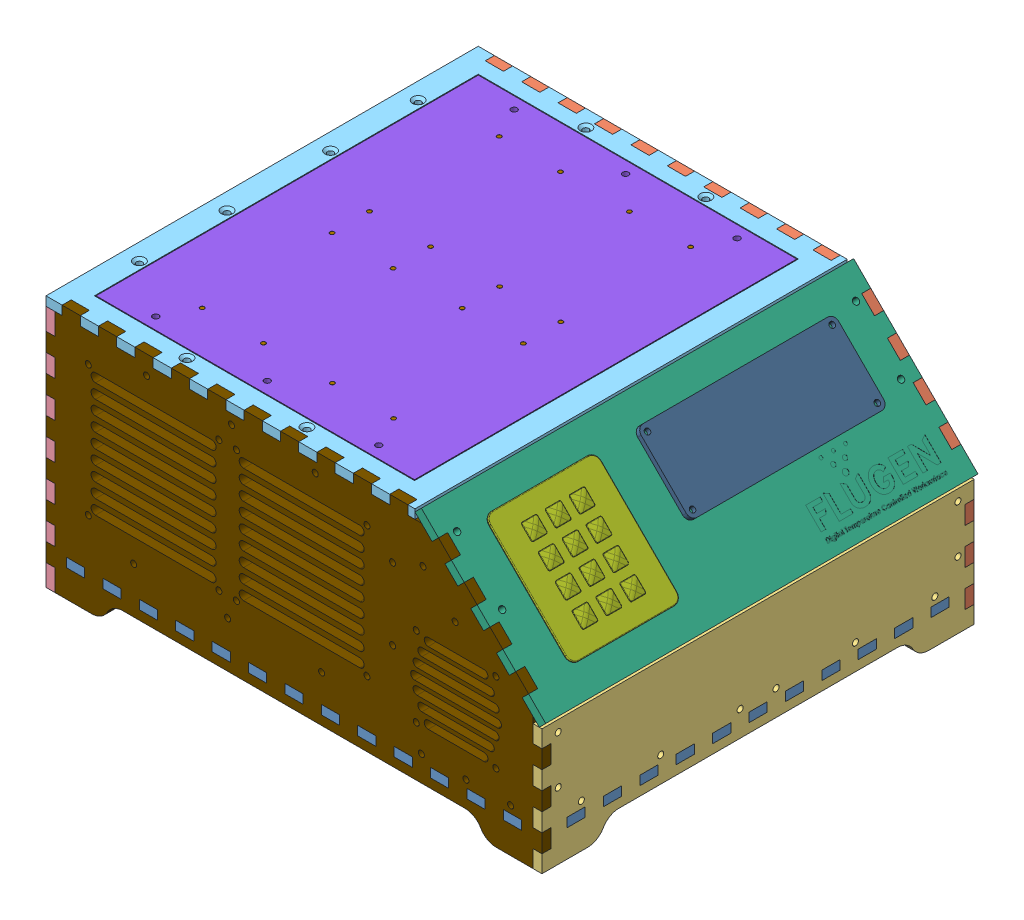
SolidWorks assembly REV 4 FINAL, configuration Default. Lengths in mm.
Overall size (313.8 160.95 271.43).
121 component instances, 55 part files, 109 mates.
Components (placement in the parent):
- Bottom R4-1: Bottom R4 [Default] at (-523.6995 354.7176 400.1225) x (1 0 0) z (0 -1 0) size (311.43 271.43 5.71)
- Side R4-2: Side R4 [Default] at (104.8725 308.9994 422.9797) size (311.43 158.58 5.71)
- Front R4-1: Front R4 [Default] at (420.9905 -621.4044 400.1225) x (0 1 0) z (1 0 0) size (78.82 271.43 5.71)
- Back R4-1: Back R4 [Default] at (115.2765 1867.4724 717.2667) x (0 -1 0) z (1 0 0) size (152.86 271.43 5.71)
- Top R4-1: Top R4 [Default] at (1495.1765 490.4374 717.2667) x (-1 0 0) z (0 -1 0) size (231.68 271.43 5.71)
- Console R4-1: Console R4 [Default] at (-380.8231 1224.6196 400.1222) x (0.707107 -0.707107 0) z (-0.707107 -0.707107 0) size (110.42 271.43 5.71)
- Peltier Assembly 3.0-1: Peltier Assembly 3.0 [Default] at (230.9915 490.4374 558.6945) x (-1 0 0) z (0 0 1) size (200 67.45 240)
  - Heatsink 3.0-1: Heatsink 3.0 [Default] at (-40.875 6 -52.5) x (-1 0 0) z (0 0 -1) size (78.2 61.32 89)
  - Heatsink 3.0-2: Heatsink 3.0 [Default] at (40.875 6 52.5) x (-1 0 0) z (0 0 -1) size (78.2 61.32 89)
  - Heatsink 3.0-3: Heatsink 3.0 [Default] at (-40.875 6 52.5) x (-1 0 0) z (0 0 -1) size (78.2 61.32 89)
  - Heatsink 3.0-4: Heatsink 3.0 [Default] at (40.875 6 -52.5) x (-1 0 0) z (0 0 -1) size (78.2 61.32 89)
  - Cold plate 2.0-1: Cold plate 2.0 [Default] at (-100 0 -220) x (0 0 1) z (0 1 0) size (240 200 3)
  - 91772A162_Passivated 18-8 Stainless Steel Pan Head Phillips Screw-1: 91772A162_Passivated 18-8 Stainless Steel Pan Head Phillips Screw [91772A162] at (21.675 0 93.25) x (0.999996 0 0.002747) z (0 1 0) size (6.86 6.86 16.79)
  - 91772A162_Passivated 18-8 Stainless Steel Pan Head Phillips Screw-2: 91772A162_Passivated 18-8 Stainless Steel Pan Head Phillips Screw [91772A162] at (-21.675 0 93.25) x (0.999996 0 0.002747) z (0 1 0) size (6.86 6.86 16.79)
  - 91772A162_Passivated 18-8 Stainless Steel Pan Head Phillips Screw-3: 91772A162_Passivated 18-8 Stainless Steel Pan Head Phillips Screw [91772A162] at (-60.075 0 93.25) x (0.996452 0 -0.084158) z (0 1 0) size (6.86 6.86 16.79)
  - 91772A162_Passivated 18-8 Stainless Steel Pan Head Phillips Screw-4: 91772A162_Passivated 18-8 Stainless Steel Pan Head Phillips Screw [91772A162] at (60.075 0 93.25) x (0.999996 0 0.002747) z (0 1 0) size (6.86 6.86 16.79)
  - 91772A162_Passivated 18-8 Stainless Steel Pan Head Phillips Screw-5: 91772A162_Passivated 18-8 Stainless Steel Pan Head Phillips Screw [91772A162] at (21.675 0 11.75) x (0.999996 0 0.002747) z (0 1 0) size (6.86 6.86 16.79)
  - 91772A162_Passivated 18-8 Stainless Steel Pan Head Phillips Screw-6: 91772A162_Passivated 18-8 Stainless Steel Pan Head Phillips Screw [91772A162] at (-21.675 0 11.75) x (0.999996 0 0.002747) z (0 1 0) size (6.86 6.86 16.79)
  - 91772A162_Passivated 18-8 Stainless Steel Pan Head Phillips Screw-7: 91772A162_Passivated 18-8 Stainless Steel Pan Head Phillips Screw [91772A162] at (-60.075 0 11.75) x (0.999996 0 0.002747) z (0 1 0) size (6.86 6.86 16.79)
  - 91772A162_Passivated 18-8 Stainless Steel Pan Head Phillips Screw-8: 91772A162_Passivated 18-8 Stainless Steel Pan Head Phillips Screw [91772A162] at (21.675 0 -11.75) x (0.999996 0 0.002747) z (0 1 0) size (6.86 6.86 16.79)
  - 91772A162_Passivated 18-8 Stainless Steel Pan Head Phillips Screw-9: 91772A162_Passivated 18-8 Stainless Steel Pan Head Phillips Screw [91772A162] at (60.075 0 11.75) x (0.999996 0 0.002747) z (0 1 0) size (6.86 6.86 16.79)
  - 91772A162_Passivated 18-8 Stainless Steel Pan Head Phillips Screw-10: 91772A162_Passivated 18-8 Stainless Steel Pan Head Phillips Screw [91772A162] at (-21.675 0 -11.75) x (0.999996 0 0.002747) z (0 1 0) size (6.86 6.86 16.79)
  - 91772A162_Passivated 18-8 Stainless Steel Pan Head Phillips Screw-11: 91772A162_Passivated 18-8 Stainless Steel Pan Head Phillips Screw [91772A162] at (60.075 0 -11.75) x (0.999996 0 0.002747) z (0 1 0) size (6.86 6.86 16.79)
  - 91772A162_Passivated 18-8 Stainless Steel Pan Head Phillips Screw-12: 91772A162_Passivated 18-8 Stainless Steel Pan Head Phillips Screw [91772A162] at (-60.075 0 -11.75) x (0.999996 0 0.002747) z (0 1 0) size (6.86 6.86 16.79)
  - 91772A162_Passivated 18-8 Stainless Steel Pan Head Phillips Screw-13: 91772A162_Passivated 18-8 Stainless Steel Pan Head Phillips Screw [91772A162] at (60.075 0 -93.25) x (0.999996 0 0.002747) z (0 1 0) size (6.86 6.86 16.79)
  - 91772A162_Passivated 18-8 Stainless Steel Pan Head Phillips Screw-14: 91772A162_Passivated 18-8 Stainless Steel Pan Head Phillips Screw [91772A162] at (21.675 0 -93.25) x (0.999996 0 0.002747) z (0 1 0) size (6.86 6.86 16.79)
  - 91772A162_Passivated 18-8 Stainless Steel Pan Head Phillips Screw-15: 91772A162_Passivated 18-8 Stainless Steel Pan Head Phillips Screw [91772A162] at (-21.675 0 -93.25) x (0.893935 0 0.448197) z (0 1 0) size (6.86 6.86 16.79)
  - 91772A162_Passivated 18-8 Stainless Steel Pan Head Phillips Screw-16: 91772A162_Passivated 18-8 Stainless Steel Pan Head Phillips Screw [91772A162] at (-60.075 0 -93.25) x (0.970194 0 -0.242331) z (0 1 0) size (6.86 6.86 16.79)
  - Acrylic seperator-1: Acrylic seperator [Default] at (100 3 220) x (0 0 -1) z (0 1 0) size (240 200 3)
- PSU-1: PSU [Default] at (115.2765 360.4326 440.1944) x (0 0 1) z (-1 0 0) size (87 40 205)
- PSU adapter board-1: PSU adapter board [Default] at (368.0265 364.7526 482.5694) x (0 0 -1) z (1 0 0) size (90 17.46 103.75)
- Hot area seperator-1: Hot area seperator [Default] at (231.2577 402.6176 483.6944) x (0 0 1) z (-1 0 0) size (110 3.1 220.53)
- Hot area seperator2-1: Hot area seperator2 [Default] at (231.2577 380.2176 538.6944) size (220.53 51 3.1)
- Hot area seperator3-1: Hot area seperator3 [Default] at (337.674 419.7176 558.6947) x (0 0 -1) z (1 0 0) size (260 130 3.1)
- F9-1: F9 [Default] at (243.6345 385.427 608.0401) x (-1 0 0) z (0 0 1) size (93.27 26.59 93.52)
  - F9.STEP-1: F9.STEP [Default] at origin size (93.27 26.59 93.52)
    - F9 body.STEP-1: F9 body.STEP [Default] at (-78.1983 5.7094 50.7544) size (92.01 26.59 92.01)
    - F9 fan.STEP-1: F9 fan.STEP [Default] at (-74.2115 10.4094 -44.9134) x (-0.083202 0 0.996533) z (-0.996533 0 -0.083202) size (86.63 20 86.36)
- F9-2: F9 [Default] at (150.6345 385.427 608.0401) x (-1 0 0) z (0 0 1) size (93.27 26.59 93.52)
  - F9.STEP-1: F9.STEP [Default] at origin size (93.27 26.59 93.52)
    - F9 body.STEP-1: F9 body.STEP [Default] at (-78.1983 5.7094 50.7544) size (92.01 26.59 92.01)
    - F9 fan.STEP-1: F9 fan.STEP [Default] at (-74.2115 10.4094 -44.9134) x (-0.083202 0 0.996533) z (-0.996533 0 -0.083202) size (86.63 20 86.36)
- Side R4_no_vent-1: Side R4_no_vent [Default] at (104.8764 309.0049 688.6942) size (311.43 158.58 5.71)
- Cold plate bracket-1: Cold plate bracket [Default] at (310.9915 484.4374 428.6947) x (0 0 -1) z (-1 0 0) size (24 12.29 160)
- Cold plate bracket-2: Cold plate bracket [Default] at (150.9915 484.4374 688.6942) x (0 0 1) z (1 0 0) size (24 12.29 160)
- Cold plate rear bracket-1: Cold plate rear bracket [Default] at (120.9915 484.7224 676.1946) x (0 1 0) z (0 0 -1) size (24 9.5 115)
- Cold plate rear bracket-2: Cold plate rear bracket [Default] at (120.9915 484.7224 556.1946) x (0 1 0) z (0 0 -1) size (24 9.5 115)
- HBridge Assembly-1: HBridge Assembly [Default] at (374.4563 378.022 646.7043) x (1 0 0) z (0 1 0) size (55.5 50 87)
  - BTS7960 H-Bridge Module-1: BTS7960 H-Bridge Module [Default] at (-3.9323 23.7652 53.8628) size (51.5 49.9 42)
    - BTS7960 H-Bridge Module.step-1: BTS7960 H-Bridge Module.step [Default] at origin size (51.5 49.9 42)
      - 2Pos Terminal Block_001.step-1: 2Pos Terminal Block_001.step [Default] at (0.8 20 1.6) x (0 1 0) z (0 0 1) size (10 10.4 16.75)
      - Body_001.step-1: Body_001.step [Default] at origin size (49.5 49.8 1.6)
      - 2Pos Terminal Block_002.step-1: 2Pos Terminal Block_002.step [Default] at (10.7 20 1.6) x (0 1 0) z (0 0 1) size (10 10.4 16.75)
      - Capacitor_001.step-1: Capacitor_001.step [Default] at (-10.7672 19.837 1.6) x (0 -1 0) z (-1 0 0) size (10.12 17.5 10.12)
      - BTN7960_001.step-1: BTN7960_001.step [Default] at (5.9321 -1.893 1.6) size (10 15.38 4.4)
      - BTN7960_002.step-1: BTN7960_002.step [Default] at (-5.9827 -1.8968 1.6) size (10 15.38 4.4)
      - SOJ 20_001.step-1: SOJ 20_001.step [Default] at (17.2939 -12.0721 1.6) x (0 -1 0) z (0 0 1) size (10.85 12.9 2.4)
      - 2x4 Male Header_001.step-1: 2x4 Male Header_001.step [Default] at (5.8669 -22.8725 1.6) size (10.16 5.08 11.3)
      - Fillet.step-1: Fillet.step [Default] at origin size (51.5 31.77 22.9)
      - M2.5x6-Screw.step-1: M2.5x6-Screw.step [Default] at (-13.3 -2.4 2) size (4.5 4.5 6)
      - M2.5x6-Screw.step-2: M2.5x6-Screw.step [Default] at (13.7 -2.4 2) size (4.5 4.5 6)
      - 0805 Resistor_001.step-1: 0805 Resistor_001.step [Default] at (9.9588 -15.7217 1.6) x (0 -1 0) z (0 0 1) size (2 1.25 0.5)
      - 0805 Resistor_002.step-1: 0805 Resistor_002.step [Default] at (7.9588 -15.7217 1.6) x (0 -1 0) z (0 0 1) size (2 1.25 0.5)
      - 0805 Resistor_003.step-1: 0805 Resistor_003.step [Default] at (5.9588 -15.7217 1.6) x (0 -1 0) z (0 0 1) size (2 1.25 0.5)
      - 0805 Resistor_004.step-1: 0805 Resistor_004.step [Default] at (3.9588 -15.7217 1.6) x (0 -1 0) z (0 0 1) size (2 1.25 0.5)
      - 0805 Resistor_005.step-1: 0805 Resistor_005.step [Default] at (1.9588 -15.7217 1.6) x (0 -1 0) z (0 0 1) size (2 1.25 0.5)
      - 0805 Resistor_006.step-1: 0805 Resistor_006.step [Default] at (-0.0412 -15.7217 1.6) x (0 -1 0) z (0 0 1) size (2 1.25 0.5)
      - 0805 Resistor_007.step-1: 0805 Resistor_007.step [Default] at (-2.0412 -15.7217 1.6) x (0 -1 0) z (0 0 1) size (2 1.25 0.5)
      - 0805 Resistor_008.step-1: 0805 Resistor_008.step [Default] at (-4.0412 -15.7217 1.6) x (0 -1 0) z (0 0 1) size (2 1.25 0.5)
  - BTS7960 H-Bridge Module-2: BTS7960 H-Bridge Module [Default] at (-3.9323 23.7652 8.8628) size (51.5 49.9 42)
    - BTS7960 H-Bridge Module.step-1: BTS7960 H-Bridge Module.step [Default] at origin size (51.5 49.9 42)
      - 2Pos Terminal Block_001.step-1: 2Pos Terminal Block_001.step [Default] at (0.8 20 1.6) x (0 1 0) z (0 0 1) size (10 10.4 16.75)
      - Body_001.step-1: Body_001.step [Default] at origin size (49.5 49.8 1.6)
      - 2Pos Terminal Block_002.step-1: 2Pos Terminal Block_002.step [Default] at (10.7 20 1.6) x (0 1 0) z (0 0 1) size (10 10.4 16.75)
      - Capacitor_001.step-1: Capacitor_001.step [Default] at (-10.7672 19.837 1.6) x (0 -1 0) z (-1 0 0) size (10.12 17.5 10.12)
      - BTN7960_001.step-1: BTN7960_001.step [Default] at (5.9321 -1.893 1.6) size (10 15.38 4.4)
      - BTN7960_002.step-1: BTN7960_002.step [Default] at (-5.9827 -1.8968 1.6) size (10 15.38 4.4)
      - SOJ 20_001.step-1: SOJ 20_001.step [Default] at (17.2939 -12.0721 1.6) x (0 -1 0) z (0 0 1) size (10.85 12.9 2.4)
      - 2x4 Male Header_001.step-1: 2x4 Male Header_001.step [Default] at (5.8669 -22.8725 1.6) size (10.16 5.08 11.3)
      - Fillet.step-1: Fillet.step [Default] at origin size (51.5 31.77 22.9)
      - M2.5x6-Screw.step-1: M2.5x6-Screw.step [Default] at (-13.3 -2.4 2) size (4.5 4.5 6)
      - M2.5x6-Screw.step-2: M2.5x6-Screw.step [Default] at (13.7 -2.4 2) size (4.5 4.5 6)
      - 0805 Resistor_001.step-1: 0805 Resistor_001.step [Default] at (9.9588 -15.7217 1.6) x (0 -1 0) z (0 0 1) size (2 1.25 0.5)
      - 0805 Resistor_002.step-1: 0805 Resistor_002.step [Default] at (7.9588 -15.7217 1.6) x (0 -1 0) z (0 0 1) size (2 1.25 0.5)
      - 0805 Resistor_003.step-1: 0805 Resistor_003.step [Default] at (5.9588 -15.7217 1.6) x (0 -1 0) z (0 0 1) size (2 1.25 0.5)
      - 0805 Resistor_004.step-1: 0805 Resistor_004.step [Default] at (3.9588 -15.7217 1.6) x (0 -1 0) z (0 0 1) size (2 1.25 0.5)
      - 0805 Resistor_005.step-1: 0805 Resistor_005.step [Default] at (1.9588 -15.7217 1.6) x (0 -1 0) z (0 0 1) size (2 1.25 0.5)
      - 0805 Resistor_006.step-1: 0805 Resistor_006.step [Default] at (-0.0412 -15.7217 1.6) x (0 -1 0) z (0 0 1) size (2 1.25 0.5)
      - 0805 Resistor_007.step-1: 0805 Resistor_007.step [Default] at (-2.0412 -15.7217 1.6) x (0 -1 0) z (0 0 1) size (2 1.25 0.5)
      - 0805 Resistor_008.step-1: 0805 Resistor_008.step [Default] at (-4.0412 -15.7217 1.6) x (0 -1 0) z (0 0 1) size (2 1.25 0.5)
  - H Bridge mount-1: H Bridge mount [Default] at (-33.6823 -1.2348 58.4628) size (13 50 60)
- NF A6x25-1: NF A6x25 [Default] at (372.774 399.7176 662.6945) x (1 0 0) z (0 -1 0) size (64.02 26 64.02)
  - NF A6x25.step-1: NF A6x25.step [Default] at origin size (64.02 26 64.02)
    - Component1.step-1: Component1.step [Default] at (0 13 0) x (1 0 0) z (0 0 -1) size (64.02 25.02 64.02)
    - Component2.step-1: Component2.step [Default] at (0 11 0.7708) x (1 0 0) z (0 0 -1) size (59.47 16.42 59.01)
    - Component3.step-1: Component3.step [Default] at (0 13 0) x (1 0 0) z (0 0 -1) size (58 26 58)
- Keypad-1: Keypad [Default] at (417.253 426.5435 667.3444) x (0 0 -1) z (0.707107 -0.707107 0) size (70 4.98 77)
- F9-3: F9 [Default] at (150.6345 420.683 657.9849) x (-1 0 0) z (0 1 0) size (93.27 26.59 93.52)
  - F9.STEP-1: F9.STEP [Default] at origin size (93.27 26.59 93.52)
    - F9 body.STEP-1: F9 body.STEP [Default] at (-78.1983 5.7094 50.7544) size (92.01 26.59 92.01)
    - F9 fan.STEP-1: F9 fan.STEP [Default] at (-74.2115 10.4094 -44.9134) x (-0.083202 0 0.996533) z (-0.996533 0 -0.083202) size (86.63 20 86.36)
- F9-4: F9 [Default] at (243.6345 420.683 657.9849) x (-1 0 0) z (0 1 0) size (93.27 26.59 93.52)
  - F9.STEP-1: F9.STEP [Default] at origin size (93.27 26.59 93.52)
    - F9 body.STEP-1: F9 body.STEP [Default] at (-78.1983 5.7094 50.7544) size (92.01 26.59 92.01)
    - F9 fan.STEP-1: F9 fan.STEP [Default] at (-74.2115 10.4094 -44.9134) x (-0.083202 0 0.996533) z (-0.996533 0 -0.083202) size (86.63 20 86.36)
- LCD assembly-1: LCD assembly [Default] at (251.087 471.3274 561.0297) x (0 0 -1) z (0.707107 -0.707107 0) size (132.15 12.15 54.2)
  - LCD-1: LCD [Default] at (-11.3148 68.4651 120.5842) size (122.15 10.65 44.2)
  - LCD Housing-1: LCD Housing [Default] at origin size (132.15 12.15 54.2)
- Window for LCD-1: Window for LCD [Default] at origin size (36.15 36.15 124)
- PSU bracket-2: PSU bracket [Default] at (139.3327 354.7176 538.6944) x (0 -1 0) z (1 0 0) size (24 16.25 180)
- Middle and rear bracket-1: Middle and rear bracket [Default] at (337.674 354.7176 682.7445) x (0 -1 0) z (0 0 -1) size (24 12 135)
- Middle and rear bracket-2: Middle and rear bracket [Default] at (120.9915 354.7176 547.7445) x (0 -1 0) z (0 0 1) size (24 12 135)
- PSU bracket-3: PSU bracket [Default] at (319.3327 354.7176 428.6947) x (0 -1 0) z (-1 0 0) size (24 16.25 180)
- Left rear bracket-4: Left rear bracket [Default] at (139.3327 354.7176 688.6942) x (0 -1 0) z (1 0 0) size (24 11.25 180)
- insulator bracket-1: insulator bracket [Default] at (319.3327 408.7176 544.7944) x (0 1 0) z (-1 0 0) size (17 17 180)
- Rear right corner-1: Rear right corner [Default] at (139.7035 405.7176 428.6947) x (0 0 -1) z (1 0 0) size (110 74 217.44)
- front left bracket-1: front left bracket [Default] at (337.674 476.72 688.6942) x (0 0 1) z (0 -1 0) size (24 9.5 90)
- front bottom bracket-1: front bottom bracket [Default] at (420.9905 354.7176 447.411) size (95 59 128.72)
- front bottom bracket left ACTUAL-1: front bottom bracket left ACTUAL [Default] at (420.9905 354.7176 449.9783) size (75 59 128.72)
- Console brackets-1: Console brackets [Default] at (394.2715 441.4428 688.6945) x (0.707107 0.707107 0) z (-0.707107 0.707107 0) size (20 9.5 60)
- Console brackets-2: Console brackets [Default] at (351.8451 483.8598 428.6947) x (0.707107 0.707107 0) z (0.707107 -0.707107 0) size (20 9.5 60)
Mates (geometry in assembly coordinates):
- Coincident4: coincident anti-aligned: plane of Bottom R4-1 through (368.1475 349.0026 428.6947) normal (0 0 -1); plane of Side R4-2 through (104.8725 308.9994 428.6947) normal (0 0 1)
- Coincident5: coincident anti-aligned: plane of Bottom R4-1 through (-523.6995 349.0026 400.1225) normal (0 -1 0); plane of Side R4-2 through (408.1475 349.0026 428.6947) normal (0 1 0)
- Coincident6: coincident anti-aligned: plane of Bottom R4-1 through (413.8635 349.0026 422.98) normal (1 0 0); plane of Side R4-2 through (413.8635 354.7173 428.6947) normal (-1 0 0)
- Coincident7: coincident anti-aligned: plane of Bottom R4-1 through (420.9905 349.0026 564.4095) normal (1 0 0); plane of Front R4-1 through (420.9905 -621.4044 400.1225) normal (-1 0 0)
- Coincident8: coincident anti-aligned: plane of Bottom R4-1 through (-523.6995 349.0026 400.1225) normal (0 -1 0); plane of Front R4-1 through (426.7055 349.0026 672.9945) normal (0 1 0)
- Coincident9: coincident anti-aligned: plane of Bottom R4-1 through (420.9905 349.0026 667.2805) normal (0 0 -1); plane of Front R4-1 through (426.7055 354.7176 667.2805) normal (0 0 1)
- Coincident10: coincident anti-aligned: plane of Bottom R4-1 through (120.9915 349.0026 575.8405) normal (-1 0 0); plane of Back R4-1 through (120.9915 1867.4724 717.2667) normal (1 0 0)
- Coincident14: coincident aligned: plane of Back R4-1 through (115.2765 1867.4724 717.2667) normal (-1 0 0); plane of Top R4-1 through (115.2765 484.7224 428.6947) normal (-1 0 0)
- Coincident21: coincident aligned: plane of Top R4-1 through (1495.1765 490.4374 717.2667) normal (0 1 0); plane of Peltier Assembly 3.0-1/Cold plate 2.0-1 through (230.9915 490.4374 558.6945) normal (0 1 0)
- Distance1: distance = 10 mm anti-aligned: plane of Peltier Assembly 3.0-1/Cold plate 2.0-1 through (130.9915 487.4374 438.6945) normal (-1 0 0); plane of Back R4-1 through (120.9915 1867.4724 717.2667) normal (1 0 0)
- Width3: width aligned: plane of PSU adapter board-1 through (320.2765 366.8076 515.0694) normal (0 0 -1); plane of PSU adapter board-1 through (320.2765 366.8076 450.0694) normal (0 0 1); plane of PSU-1 through (320.2765 366.4326 449.9444) normal (0 0 -1); plane of PSU-1 through (320.2765 366.4326 515.1944) normal (0 0 1)
- Width4: width aligned: plane of PSU-1 through (320.2765 364.7826 515.1944) normal (0 -1 0); plane of PSU-1 through (320.2765 366.4326 515.1944) normal (0 1 0); plane of PSU adapter board-1 through (320.2765 366.8076 450.0694) normal (0 -1 0); plane of PSU adapter board-1 through (320.2765 364.4076 450.0694) normal (0 1 0)
- Coincident22: coincident anti-aligned: plane of PSU-1 through (320.2765 360.4326 440.1944) normal (1 0 0); plane of PSU adapter board-1 through (320.2765 364.7526 482.5694) normal (-1 0 0)
- Coincident23: coincident aligned: plane of Back R4-1 through (115.2765 1867.4724 717.2667) normal (-1 0 0); plane of PSU-1 through (115.2765 398.9826 482.6444) normal (-1 0 0)
- Distance4: distance = 5.715 mm anti-aligned: plane of PSU-1 through (149.2765 360.4326 440.1944) normal (0 -1 0); plane of Bottom R4-1 through (-523.6995 354.7176 400.1225) normal (0 1 0)
- Coincident29: coincident anti-aligned: plane of Back R4-1 through (120.9915 1867.4724 717.2667) normal (1 0 0); plane of Hot area seperator-1 through (120.9915 405.7176 428.6944) normal (-1 0 0)
- Coincident30: coincident anti-aligned: plane of Side R4-2 through (104.8725 308.9994 428.6947) normal (0 0 1); plane of Hot area seperator-1 through (341.524 405.7176 428.6944) normal (0 0 -1)
- Coincident31: coincident anti-aligned: plane of Bottom R4-1 through (-523.6995 354.7176 400.1225) normal (0 1 0); plane of Hot area seperator2-1 through (120.9915 354.7176 541.7944) normal (0 -1 0)
- Coincident32: coincident anti-aligned: plane of Back R4-1 through (120.9915 1867.4724 717.2667) normal (1 0 0); plane of Hot area seperator2-1 through (120.9915 354.7176 541.7944) normal (-1 0 0)
- Coincident33: coincident anti-aligned: plane of Hot area seperator-1 through (341.524 405.7176 538.6944) normal (0 0 1); plane of Hot area seperator2-1 through (231.2577 380.2176 538.6944) normal (0 0 -1)
- Coincident34: coincident anti-aligned: plane of Side R4-2 through (104.8725 308.9994 428.6947) normal (0 0 1); plane of Hot area seperator3-1 through (340.774 405.7176 428.6947) normal (0 0 -1)
- Coincident35: coincident anti-aligned: plane of Hot area seperator-1 through (231.2577 405.7176 483.6944) normal (0 1 0); plane of Hot area seperator3-1 through (340.774 405.7176 428.6947) normal (0 -1 0)
- Width5: width anti-aligned: plane of Top R4-1 through (331.4915 484.7224 679.1945) normal (-1 0 0); plane of Top R4-1 through (346.9565 484.7224 428.6947) normal (1 0 0); plane of Hot area seperator3-1 through (340.774 419.7176 558.6947) normal (1 0 0); plane of Hot area seperator3-1 through (337.674 419.7176 558.6947) normal (-1 0 0)
- Distance6: distance = 1 mm anti-aligned: plane of F9-1/F9.STEP-1/F9 body.STEP-1 through (229.8327 354.7176 571.7944) normal (-1 0 0); plane of F9-2/F9.STEP-1/F9 body.STEP-1 through (228.8327 354.7176 612.7944) normal (1 0 0)
- Coincident37: coincident aligned: plane of F9-1/F9.STEP-1/F9 body.STEP-1 through (275.8327 354.7176 658.7944) normal (0 0 1); plane of F9-2/F9.STEP-1/F9 body.STEP-1 through (182.8327 354.7176 658.7944) normal (0 0 1)
- Coincident38: coincident aligned: plane of F9-1/F9.STEP-1/F9 body.STEP-1 through (234.8327 379.7176 571.7944) normal (0 1 0); plane of F9-2/F9.STEP-1/F9 body.STEP-1 through (141.8327 379.7176 571.7944) normal (0 1 0)
- Coincident40: coincident anti-aligned: plane of Bottom R4-1 through (-523.6995 354.7176 400.1225) normal (0 1 0); plane of F9-1/F9.STEP-1/F9 body.STEP-1 through (275.8327 354.7176 612.7944) normal (0 -1 0)
- Width7: width anti-aligned: plane of F9-2/F9.STEP-1/F9 body.STEP-1 through (136.8327 354.7176 571.7944) normal (-1 0 0); plane of Back R4-1 through (321.8327 354.7176 612.7944) normal (1 0 0); plane of F9-1/F9.STEP-1/F9 body.STEP-1 through (120.9915 1867.4724 717.2667) normal (1 0 0); plane of Hot area seperator3-1 through (337.674 419.7176 558.6947) normal (-1 0 0)
- Coincident41: coincident aligned: plane of Back R4-1 through (115.2765 1867.4724 717.2667) normal (-1 0 0); plane of Side R4_no_vent-1 through (115.2765 471.1579 694.4092) normal (-1 0 0)
- Coincident42: coincident aligned: plane of Back R4-1 through (120.9915 436.8624 694.4092) normal (0 0 1); plane of Side R4_no_vent-1 through (104.8764 309.0049 694.4092) normal (0 0 1)
- Coincident43: coincident aligned: plane of Back R4-1 through (120.9915 331.8624 665.8342) normal (0 -1 0); plane of Side R4_no_vent-1 through (143.8513 331.8624 694.4092) normal (0 -1 0)
- Coincident45: coincident anti-aligned: plane of Side R4-2 through (104.8725 308.9994 428.6947) normal (0 0 1); plane of Cold plate bracket-1 through (150.9915 484.4374 428.6947) normal (0 0 -1)
- Coincident47: coincident anti-aligned: plane of Side R4-2 through (104.8725 308.9994 428.6947) normal (0 0 1); plane of Back R4-1 through (120.9915 459.7224 428.6947) normal (0 0 -1)
- Coincident48: coincident: plane of Side R4-2 through (120.9873 471.1524 428.6947) normal (0 1 0); line of Back R4-1 through (115.2765 471.1524 428.6947) axis (0 0 -1)
- Coincident49: coincident anti-aligned: plane of Back R4-1 through (120.9915 484.7224 428.6947) normal (0 1 0); plane of Top R4-1 through (1495.1765 484.7224 717.2667) normal (0 -1 0)
- Coincident50: coincident aligned: plane of Side R4-2 through (104.8725 308.9994 422.9797) normal (0 0 -1); plane of Top R4-1 through (120.9965 484.7224 422.9797) normal (0 0 -1)
- Width9: width anti-aligned: plane of Peltier Assembly 3.0-1/Cold plate 2.0-1 through (130.9915 487.4374 438.6945) normal (0 0 -1); plane of Top R4-1 through (130.9915 487.4374 678.6945) normal (0 0 1); plane of Peltier Assembly 3.0-1/Cold plate 2.0-1 through (120.9965 484.7224 694.4092) normal (0 0 1); plane of Top R4-1 through (120.9965 484.7224 422.9797) normal (0 0 -1)
- Coincident51: coincident anti-aligned: plane of Console R4-1 through (-384.8642 1220.5785 400.1222) normal (-0.707107 -0.707107 0); plane of Side R4_no_vent-1 through (406.1974 429.5169 694.4092) normal (0.707107 0.707107 0)
- Coincident52: coincident aligned: plane of Console R4-1 through (406.1974 429.5169 694.4092) normal (0 0 1); plane of Side R4_no_vent-1 through (104.8764 309.0049 694.4092) normal (0 0 1)
- Coincident53: coincident anti-aligned: plane of Console R4-1 through (406.1974 429.5169 688.6942) normal (0.707107 -0.707107 0); plane of Side R4_no_vent-1 through (410.2384 433.5579 694.4092) normal (-0.707107 0.707107 0)
- Coincident55: coincident anti-aligned: plane of Side R4_no_vent-1 through (104.8764 309.0049 688.6942) normal (0 0 -1); plane of Cold plate bracket-2 through (310.9915 484.4374 688.6942) normal (0 0 1)
- Coincident56: coincident anti-aligned: plane of Peltier Assembly 3.0-1/Acrylic seperator-1 through (230.9915 484.4374 558.6945) normal (0 -1 0); plane of Cold plate bracket-1 through (150.9915 484.4374 452.6947) normal (0 1 0)
- Coincident57: coincident anti-aligned: plane of Peltier Assembly 3.0-1/Acrylic seperator-1 through (230.9915 484.4374 558.6945) normal (0 -1 0); plane of Cold plate bracket-2 through (310.9915 484.4374 664.6942) normal (0 1 0)
- Distance7: distance = 5 mm anti-aligned: plane of Cold plate rear bracket-1 through (126.9915 473.7224 561.1946) normal (0 0 -1); plane of Cold plate rear bracket-2 through (126.9915 473.7224 556.1946) normal (0 0 1)
- Coincident59: coincident aligned: plane of Cold plate rear bracket-1 through (120.9915 484.7224 561.1946) normal (0 1 0); plane of Cold plate rear bracket-2 through (120.9915 484.7224 441.1946) normal (0 1 0)
- Coincident60: coincident aligned: plane of Cold plate rear bracket-1 through (130.4915 484.7224 561.1946) normal (1 0 0); plane of Cold plate rear bracket-2 through (130.4915 484.7224 441.1946) normal (1 0 0)
- Coincident61: coincident anti-aligned: plane of Back R4-1 through (120.9915 1867.4724 717.2667) normal (1 0 0); plane of Cold plate rear bracket-1 through (120.9915 460.7224 561.1946) normal (-1 0 0)
- Coincident62: coincident anti-aligned: plane of Top R4-1 through (1495.1765 484.7224 717.2667) normal (0 -1 0); plane of Cold plate rear bracket-2 through (120.9915 484.7224 441.1946) normal (0 1 0)
- Width10: width aligned: plane of Cold plate rear bracket-1 through (126.9915 473.7224 676.1946) normal (0 0 1); plane of Cold plate rear bracket-2 through (126.9915 473.7224 441.1946) normal (0 0 -1); plane of Side R4-2 through (104.8725 308.9994 428.6947) normal (0 0 1); plane of Back R4-1 through (120.9915 471.1524 688.6945) normal (0 0 1)
- Coincident63: coincident anti-aligned: plane of Hot area seperator3-1 through (340.774 419.7176 558.6947) normal (1 0 0); plane of HBridge Assembly-1/H Bridge mount-1 through (340.774 436.4848 597.9391) normal (-1 0 0)
- Coincident64: coincident anti-aligned: plane of Side R4_no_vent-1 through (104.8764 309.0049 688.6942) normal (0 0 -1); plane of NF A6x25-1/NF A6x25.step-1/Component3.step-1 through (397.774 424.7176 688.6945) normal (0 0 1)
- Distance8: distance = 2 mm: plane of Hot area seperator3-1 through (340.774 419.7176 558.6947) normal (1 0 0); line of NF A6x25-1/NF A6x25.step-1/Component1.step-1 through (342.774 373.7176 663.1945) axis (0 1 0)
- Distance9: distance = 15 mm anti-aligned: plane of NF A6x25-1/NF A6x25.step-1/Component1.step-1 through (342.774 369.7176 663.1945) normal (0 -1 0); plane of Bottom R4-1 through (-523.6995 354.7176 400.1225) normal (0 1 0)
- Parallel1: parallel anti-aligned: plane of Bottom R4-1 through (-523.6995 354.7176 400.1225) normal (0 1 0); plane of HBridge Assembly-1/BTS7960 H-Bridge Module-1/BTS7960 H-Bridge Module.step-1/Body_001.step-1 through (370.524 431.8848 622.9391) normal (0 -1 0)
- Coincident70: coincident anti-aligned: plane of Console R4-1 through (-380.8231 1224.6196 400.1222) normal (0.707107 0.707107 0); plane of Keypad-1 through (413.7175 430.079 662.3444) normal (-0.707107 -0.707107 0)
- Parallel4: parallel aligned: plane of Console R4-1 through (425.0276 410.6866 688.6942) normal (0.707107 -0.707107 0); plane of Keypad-1 through (417.9601 427.2506 662.3444) normal (0.707107 -0.707107 0)
- Distance11: distance = 25 mm: plane of Hot area seperator2-1 through (231.2577 380.2176 541.7944) normal (0 0 1); line of F9-2/F9.STEP-1/F9 body.STEP-1 through (141.8327 379.7176 566.7944) axis (1 0 0)
- Coincident73: coincident aligned: plane of F9-3/F9.STEP-1/F9 body.STEP-1 through (141.8327 384.4374 663.6942) normal (0 0 -1); plane of F9-4/F9.STEP-1/F9 body.STEP-1 through (234.8327 384.4374 663.6942) normal (0 0 -1)
- Coincident74: coincident aligned: plane of F9-3/F9.STEP-1/F9 body.STEP-1 through (182.8327 471.4374 688.6942) normal (0 1 0); plane of F9-4/F9.STEP-1/F9 body.STEP-1 through (275.8327 471.4374 688.6942) normal (0 1 0)
- Distance12: distance = 1 mm anti-aligned: plane of F9-4/F9.STEP-1/F9 body.STEP-1 through (229.8327 384.4374 688.6942) normal (-1 0 0); plane of F9-3/F9.STEP-1/F9 body.STEP-1 through (228.8327 425.4374 688.6942) normal (1 0 0)
- Coincident75: coincident anti-aligned: plane of Side R4_no_vent-1 through (104.8764 309.0049 688.6942) normal (0 0 -1); plane of F9-3/F9.STEP-1/F9 body.STEP-1 through (182.8327 425.4374 688.6942) normal (0 0 1)
- Coincident76: coincident aligned: plane of F9-2/F9.STEP-1/F9 body.STEP-1 through (136.8327 354.7176 571.7944) normal (-1 0 0); plane of F9-3/F9.STEP-1/F9 body.STEP-1 through (136.8327 384.4374 688.6942) normal (-1 0 0)
- Distance13: distance = 1 mm anti-aligned: plane of Cold plate bracket-2 through (310.9915 472.4374 688.6942) normal (0 -1 0); plane of F9-3/F9.STEP-1/F9 body.STEP-1 through (182.8327 471.4374 688.6942) normal (0 1 0)
- Coincident79: coincident anti-aligned: plane of Console R4-1 through (-384.8642 1220.5785 400.1222) normal (-0.707107 -0.707107 0); plane of LCD assembly-1/LCD Housing-1 through (307.7369 527.9774 561.0297) normal (0.707107 0.707107 0)
- Parallel5: parallel aligned: plane of Console R4-1 through (425.0276 410.6866 688.6942) normal (0.707107 -0.707107 0); plane of LCD assembly-1/LCD Housing-1 through (286.5952 329.2329 577.3444) normal (0.707107 -0.707107 0)
- Coincident80: coincident: plane of Bottom R4-1 through (-523.6995 354.7176 400.1225) normal (0 1 0); line of Hot area seperator3-1 through (340.774 354.7176 688.6947) axis (0 0 -1)
- Coincident81: coincident anti-aligned: plane of Bottom R4-1 through (-523.6995 354.7176 400.1225) normal (0 1 0); plane of PSU bracket-2 through (319.3327 354.7176 538.6944) normal (0 -1 0)
- Coincident84: coincident anti-aligned: plane of Back R4-1 through (120.9915 1867.4724 717.2667) normal (1 0 0); plane of Middle and rear bracket-2 through (120.9915 378.7176 682.7445) normal (-1 0 0)
- Width12: width aligned: plane of Hot area seperator2-1 through (231.2577 380.2176 541.7944) normal (0 0 1); plane of Middle and rear bracket-2 through (128.1135 349.0026 688.6945) normal (0 0 1); plane of Bottom R4-1 through (126.9915 365.7176 682.7445) normal (0 0 1); plane of Middle and rear bracket-2 through (126.9915 365.7176 547.7445) normal (0 0 -1)
- Coincident85: coincident anti-aligned: plane of Bottom R4-1 through (-523.6995 354.7176 400.1225) normal (0 1 0); plane of Middle and rear bracket-2 through (120.9915 354.7176 682.7445) normal (0 -1 0)
- Coincident86: coincident anti-aligned: plane of Bottom R4-1 through (-523.6995 354.7176 400.1225) normal (0 1 0); plane of Middle and rear bracket-1 through (337.674 354.7176 547.7445) normal (0 -1 0)
- Coincident87: coincident anti-aligned: plane of Hot area seperator3-1 through (337.674 419.7176 558.6947) normal (-1 0 0); plane of Middle and rear bracket-1 through (337.674 378.7176 547.7445) normal (1 0 0)
- Coincident88: coincident aligned: plane of Middle and rear bracket-1 through (331.674 365.7176 682.7445) normal (0 0 1); plane of Middle and rear bracket-2 through (126.9915 365.7176 682.7445) normal (0 0 1)
- Width13: width aligned: plane of PSU-1 through (149.2765 360.4326 440.1944) normal (0 0 -1); plane of Hot area seperator2-1 through (149.2765 360.4326 527.1944) normal (0 0 1); plane of PSU-1 through (231.2577 380.2176 538.6944) normal (0 0 -1); plane of Side R4-2 through (104.8725 308.9994 428.6947) normal (0 0 1)
- Coincident89: coincident anti-aligned: plane of Hot area seperator2-1 through (231.2577 380.2176 538.6944) normal (0 0 -1); plane of PSU bracket-2 through (319.3327 378.7176 538.6944) normal (0 0 1)
- Coincident91: coincident anti-aligned: plane of Side R4-2 through (104.8725 308.9994 428.6947) normal (0 0 1); plane of PSU bracket-3 through (139.3327 378.7176 428.6947) normal (0 0 -1)
- Coincident92: coincident anti-aligned: plane of Bottom R4-1 through (-523.6995 354.7176 400.1225) normal (0 1 0); plane of PSU bracket-3 through (139.3327 354.7176 428.6947) normal (0 -1 0)
- Coincident93: coincident aligned: plane of PSU bracket-2 through (139.3327 365.7176 532.6944) normal (-1 0 0); plane of PSU bracket-3 through (139.3327 365.7176 434.6947) normal (-1 0 0)
- Coincident94: coincident anti-aligned: plane of Bottom R4-1 through (-523.6995 354.7176 400.1225) normal (0 1 0); plane of Left rear bracket-4 through (319.3327 354.7176 688.6942) normal (0 -1 0)
- Coincident95: coincident anti-aligned: plane of Side R4_no_vent-1 through (104.8764 309.0049 688.6942) normal (0 0 -1); plane of Left rear bracket-4 through (319.3327 378.7176 688.6942) normal (0 0 1)
- Width14: width aligned: plane of Left rear bracket-4 through (139.3327 365.7176 682.6942) normal (-1 0 0); plane of Hot area seperator3-1 through (319.3327 365.7176 682.6942) normal (1 0 0); plane of Left rear bracket-4 through (337.674 419.7176 558.6947) normal (-1 0 0); plane of Side R4_no_vent-1 through (120.9912 414.0079 694.4092) normal (-1 0 0)
- Coincident96: coincident aligned: plane of PSU bracket-2 through (139.3327 365.7176 532.6944) normal (-1 0 0); plane of Left rear bracket-4 through (139.3327 365.7176 682.6942) normal (-1 0 0)
- Coincident97: coincident anti-aligned: plane of Hot area seperator-1 through (231.2577 405.7176 483.6944) normal (0 1 0); plane of insulator bracket-1 through (139.3327 405.7176 527.7944) normal (0 -1 0)
- Coincident98: coincident anti-aligned: plane of Hot area seperator2-1 through (231.2577 380.2176 541.7944) normal (0 0 1); plane of insulator bracket-1 through (139.3327 405.7176 541.7944) normal (0 0 -1)
- Width15: width anti-aligned: plane of insulator bracket-1 through (319.3327 408.7176 544.7944) normal (1 0 0); plane of insulator bracket-1 through (139.3327 408.7176 544.7944) normal (-1 0 0); plane of Hot area seperator-1 through (120.9915 405.7176 428.6944) normal (-1 0 0); plane of Hot area seperator3-1 through (337.674 419.7176 558.6947) normal (-1 0 0)
- Coincident99: coincident anti-aligned: plane of Side R4-2 through (104.8725 308.9994 428.6947) normal (0 0 1); plane of Rear right corner-1 through (329.424 405.7176 428.6947) normal (0 0 -1)
- Coincident100: coincident anti-aligned: plane of Hot area seperator-1 through (231.2577 405.7176 483.6944) normal (0 1 0); plane of Rear right corner-1 through (329.424 405.7176 437.6947) normal (0 -1 0)
- Coincident101: coincident aligned: plane of Side R4-2 through (120.9873 436.8624 428.6947) normal (-1 0 0); plane of Rear right corner-1 through (120.9873 414.7176 538.6947) normal (-1 0 0)
- Coincident104: coincident anti-aligned: plane of Side R4_no_vent-1 through (104.8764 309.0049 688.6942) normal (0 0 -1); plane of front left bracket-1 through (337.674 386.72 688.6942) normal (0 0 1)
- Coincident105: coincident anti-aligned: plane of Hot area seperator3-1 through (337.674 419.7176 558.6947) normal (-1 0 0); plane of front left bracket-1 through (337.674 386.72 664.6942) normal (1 0 0)
- Width17: width aligned: plane of front left bracket-1 through (331.674 476.72 677.6942) normal (0 1 0); plane of front left bracket-1 through (331.674 386.72 677.6942) normal (0 -1 0); plane of Middle and rear bracket-1 through (334.674 378.7176 547.7445) normal (0 1 0); plane of Top R4-1 through (1495.1765 484.7224 717.2667) normal (0 -1 0)
- Coincident106: coincident aligned: plane of Bottom R4-1 through (368.1475 349.0026 428.6947) normal (0 0 -1); plane of front bottom bracket-1 through (325.9905 363.7176 428.6947) normal (0 0 -1)
- Coincident107: coincident anti-aligned: plane of Front R4-1 through (420.9905 -621.4044 400.1225) normal (-1 0 0); plane of front bottom bracket-1 through (420.9905 354.7176 557.411) normal (1 0 0)
- Coincident108: coincident anti-aligned: plane of Bottom R4-1 through (-523.6995 354.7176 400.1225) normal (0 1 0); plane of front bottom bracket-1 through (411.9905 354.7176 557.411) normal (0 -1 0)
- Coincident112: coincident anti-aligned: plane of Front R4-1 through (420.9905 -621.4044 400.1225) normal (-1 0 0); plane of front bottom bracket left ACTUAL-1 through (420.9905 354.7176 559.9783) normal (1 0 0)
- Coincident113: coincident aligned: plane of Bottom R4-1 through (402.4375 349.0026 688.6945) normal (0 0 1); plane of front bottom bracket left ACTUAL-1 through (345.9905 363.7176 688.6945) normal (0 0 1)
- Coincident114: coincident anti-aligned: plane of Bottom R4-1 through (-523.6995 354.7176 400.1225) normal (0 1 0); plane of front bottom bracket left ACTUAL-1 through (411.9905 354.7176 559.9783) normal (0 -1 0)
- Coincident115: coincident anti-aligned: plane of Side R4_no_vent-1 through (104.8764 309.0049 688.6942) normal (0 0 -1); plane of Console brackets-1 through (337.7029 469.7271 688.6945) normal (0 0 1)
- Coincident116: coincident aligned: plane of Side R4_no_vent-1 through (373.8684 461.8459 694.4092) normal (0.707107 0.707107 0); plane of Console brackets-1 through (351.8451 483.8692 688.6945) normal (0.707107 0.707107 0)
- Distance15: distance = 4 mm: line of Console brackets-1 through (344.774 462.656 685.6945) axis (0 1 0); plane of Hot area seperator3-1 through (340.774 419.7176 558.6947) normal (1 0 0)
- Coincident118: coincident anti-aligned: plane of Side R4-2 through (104.8725 308.9994 428.6947) normal (0 0 1); plane of Console brackets-2 through (380.1293 427.2913 428.6947) normal (0 0 -1)
- Coincident119: coincident aligned: plane of Side R4-2 through (373.8645 461.8404 428.6947) normal (0.707107 0.707107 0); plane of Console brackets-2 through (394.2715 441.4334 428.6947) normal (0.707107 0.707107 0)
- Distance16: distance = 4 mm anti-aligned: plane of Console brackets-2 through (344.774 462.6466 431.6947) normal (-1 0 0); plane of Hot area seperator3-1 through (340.774 419.7176 558.6947) normal (1 0 0)
- Width18: width anti-aligned: plane of Keypad-1 through (363.5129 481.6978 662.3444) normal (-0.707107 0.707107 0); plane of Console R4-1 through (417.9601 427.2506 662.3444) normal (0.707107 -0.707107 0); plane of Keypad-1 through (425.0276 410.6866 688.6942) normal (0.707107 -0.707107 0); plane of Console R4-1 through (346.9489 488.7654 428.6944) normal (-0.707107 0.707107 0)
- Distance18: distance = 0.78 mm aligned: plane of Keypad-1 through (363.5129 481.6978 662.3444) normal (-0.707107 0.707107 0); plane of LCD assembly-1/LCD Housing-1 through (248.27 367.5581 445.1944) normal (-0.707107 0.707107 0)
- Distance19: distance = 20 mm anti-aligned: plane of LCD assembly-1/LCD Housing-1 through (248.27 367.5581 577.3444) normal (0 0 1); plane of Keypad-1 through (414.4246 430.7861 597.3444) normal (0 0 -1)
- Distance20: distance = 16.5 mm aligned: plane of LCD assembly-1/LCD Housing-1 through (286.5952 329.2329 445.1944) normal (0 0 -1); plane of Console R4-1 through (390.0329 445.6813 428.6944) normal (0 0 -1)
- Concentric1: concentric aligned: cylinder of Side R4_no_vent-1 through (284.3248 478.5799 694.4092) axis (0 0 1) radius 1.8986; cylinder of Cold plate bracket-2 through (284.3248 478.5799 682.3442) axis (0 0 1) radius 2.6162
- Concentric2: concentric aligned: cylinder of Side R4-2 through (284.3248 478.5799 422.9797) axis (0 0 -1) radius 1.8986; cylinder of Cold plate bracket-1 through (284.3248 478.5799 435.0447) axis (0 0 -1) radius 2.6162
